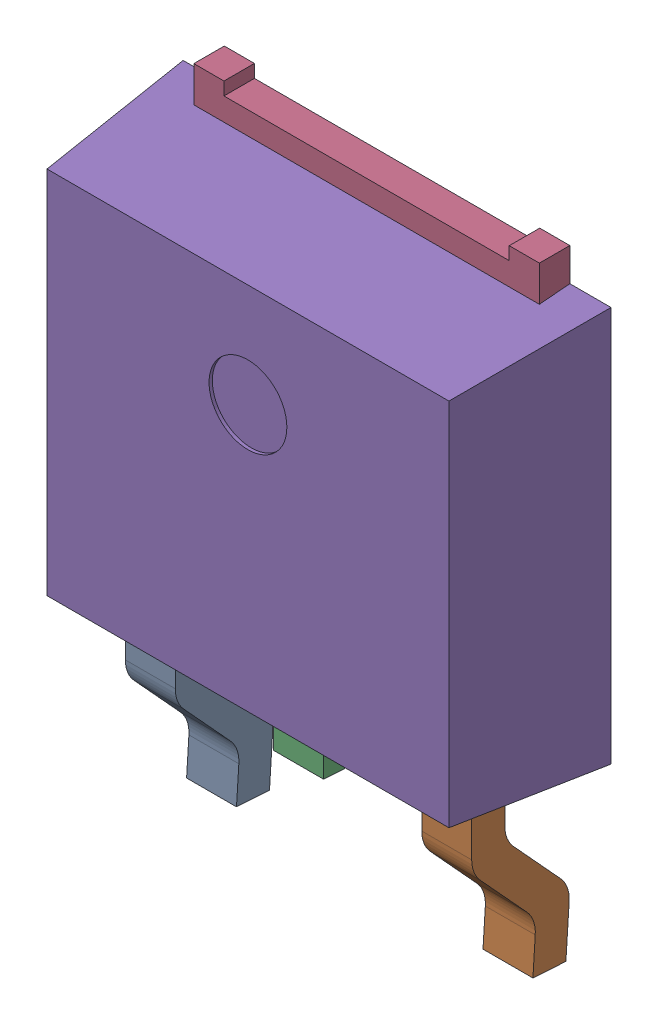
SolidWorks assembly IC9_1.step, configuration Default. Lengths in mm.
Overall size (6.6 9.53 2.3).
3 component instances, 2 part files, 0 mates.
Components (placement in the parent):
- 6348793488_1.step-3: 6348793488_1.step [Default] at (411.867 301.671 0) x (1 0 0) z (0 0 1) size (6.6 9.53 2.3)
  - Linear Pattern 01_1.step-5: Linear Pattern 01_1.step [Default] at origin size (5.34 3.53 1.5)
  - Open CASCADE STEP translator 7.5 5.121.1.2_1.step-5: Open CASCADE STEP translator 7.5 5.121.1.2_1.step [Default] at origin size (6.6 6.61 2.3)
